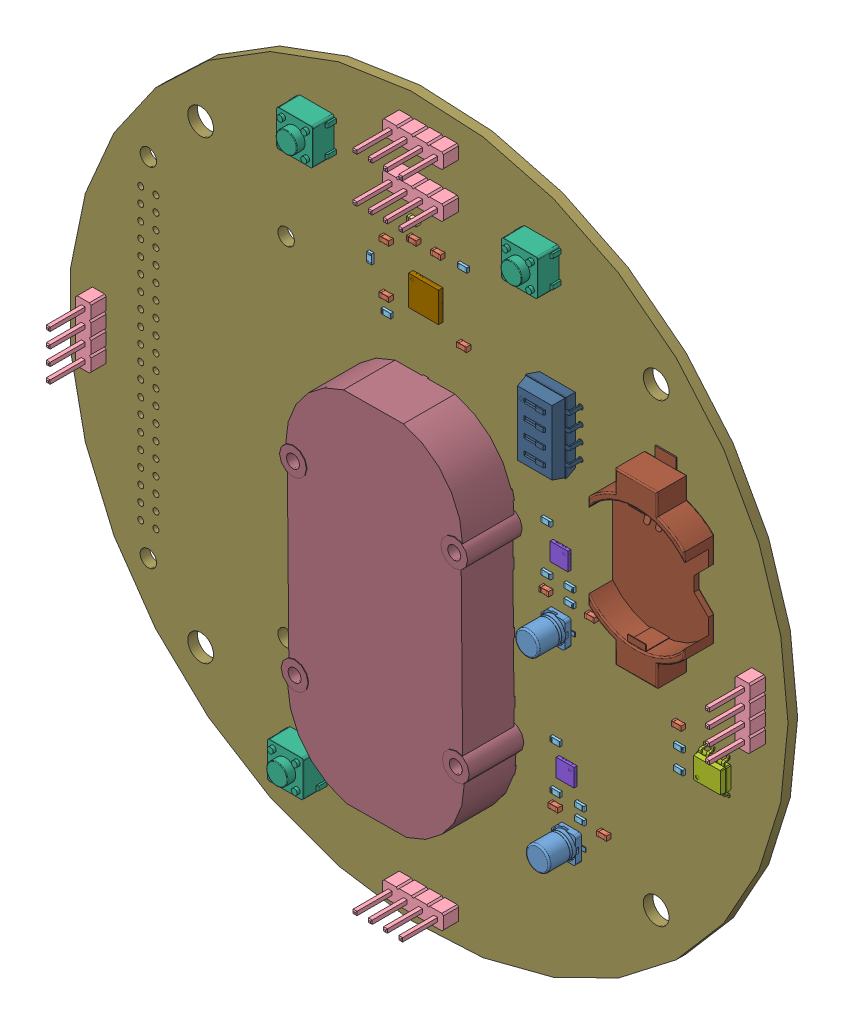
SolidWorks assembly PCB, configuration Default. Lengths in mm.
Overall size (120 120 26.3).
83 component instances, 13 part files, 8 mates.
Components (placement in the parent):
- clockclock.step-1: clockclock.step [Default] at origin size (120 120 12.04)
  - C_Elec_4x5.4.step-1: C_Elec_4x5.4.step [Default] at (21.844 -4.826 1.65) size (5.74 5.46 5.4)
    - COMPOUND.step-1: COMPOUND.step [Default] at origin size (5.74 5.46 5.4)
  - C_Elec_4x5.4.step-2: C_Elec_4x5.4.step [Default] at (23.622 -35.052 1.65) size (5.74 5.46 5.4)
    - COMPOUND.step-1: COMPOUND.step [Default] at origin size (5.74 5.46 5.4)
  - C_0603_1608Metric.step-1: C_0603_1608Metric.step [Default] at (29.718 -30.988 1.65) x (-1 0 0) z (0 0 1) size (1.6 0.8 0.8)
    - SOLID.step-1: SOLID.step [Default] at origin size (1.6 0.8 0.8)
  - C_0603_1608Metric.step-2: C_0603_1608Metric.step [Default] at (27.686 -0.508 1.65) x (-1 0 0) z (0 0 1) size (1.6 0.8 0.8)
    - SOLID.step-1: SOLID.step [Default] at origin size (1.6 0.8 0.8)
  - C_0603_1608Metric.step-3: C_0603_1608Metric.step [Default] at (42.164 -8.89 1.65) size (1.6 0.8 0.8)
    - SOLID.step-1: SOLID.step [Default] at origin size (1.6 0.8 0.8)
  - C_0603_1608Metric.step-4: C_0603_1608Metric.step [Default] at (-6.604 36.83 1.65) size (1.6 0.8 0.8)
    - SOLID.step-1: SOLID.step [Default] at origin size (1.6 0.8 0.8)
  - C_0603_1608Metric.step-5: C_0603_1608Metric.step [Default] at (-6.604 28.702 1.65) size (1.6 0.8 0.8)
    - SOLID.step-1: SOLID.step [Default] at origin size (1.6 0.8 0.8)
  - C_0603_1608Metric.step-6: C_0603_1608Metric.step [Default] at (2.032 39.116 1.65) size (1.6 0.8 0.8)
    - SOLID.step-1: SOLID.step [Default] at origin size (1.6 0.8 0.8)
  - C_0603_1608Metric.step-7: C_0603_1608Metric.step [Default] at (6.35 27.94 1.65) size (1.6 0.8 0.8)
    - SOLID.step-1: SOLID.step [Default] at origin size (1.6 0.8 0.8)
  - C_0603_1608Metric.step-8: C_0603_1608Metric.step [Default] at (-2.032 39.116 1.65) size (1.6 0.8 0.8)
    - SOLID.step-1: SOLID.step [Default] at origin size (1.6 0.8 0.8)
  - L_0603_1608Metric.step-1: L_0603_1608Metric.step [Default] at (-2.032 41.91 1.65) size (1.6 0.8 0.8)
    - SOLID-0.step-1: SOLID-0.step [Default] at origin size (1.6 0.8 0.8)
  - PinHeader_1x04_P2.54mm_Vertical.step-1: PinHeader_1x04_P2.54mm_Vertical.step [Default] at (55 3.81 1.65) size (2.54 10.16 11.54)
    - SOLID-1.step-1: SOLID-1.step [Default] at origin size (2.54 10.16 11.54)
  - PinHeader_1x04_P2.54mm_Vertical.step-2: PinHeader_1x04_P2.54mm_Vertical.step [Default] at (-3.81 55 1.65) x (0 1 0) z (0 0 1) size (2.54 10.16 11.54)
    - SOLID-1.step-1: SOLID-1.step [Default] at origin size (2.54 10.16 11.54)
  - PinHeader_1x04_P2.54mm_Vertical.step-3: PinHeader_1x04_P2.54mm_Vertical.step [Default] at (-3.81 -55 1.65) x (0 1 0) z (0 0 1) size (2.54 10.16 11.54)
    - SOLID-1.step-1: SOLID-1.step [Default] at origin size (2.54 10.16 11.54)
  - PinHeader_1x04_P2.54mm_Vertical.step-4: PinHeader_1x04_P2.54mm_Vertical.step [Default] at (-55 3.81 1.65) size (2.54 10.16 11.54)
    - SOLID-1.step-1: SOLID-1.step [Default] at origin size (2.54 10.16 11.54)
  - PinHeader_1x04_P2.54mm_Vertical.step-5: PinHeader_1x04_P2.54mm_Vertical.step [Default] at (-3.81 47.498 1.65) x (0 1 0) z (0 0 1) size (2.54 10.16 11.54)
    - SOLID-1.step-1: SOLID-1.step [Default] at origin size (2.54 10.16 11.54)
  - R_0603_1608Metric.step-1: R_0603_1608Metric.step [Default] at (25.654 -30.988 1.65) x (-1 0 0) z (0 0 1) size (1.6 0.8 0.45)
    - SOLID-2.step-1: SOLID-2.step [Default] at origin size (1.6 0.8 0.45)
  - R_0603_1608Metric.step-2: R_0603_1608Metric.step [Default] at (23.876 -0.508 1.65) x (-1 0 0) z (0 0 1) size (1.6 0.8 0.45)
    - SOLID-2.step-1: SOLID-2.step [Default] at origin size (1.6 0.8 0.45)
  - R_0603_1608Metric.step-3: R_0603_1608Metric.step [Default] at (25.654 -28.956 1.65) size (1.6 0.8 0.45)
    - SOLID-2.step-1: SOLID-2.step [Default] at origin size (1.6 0.8 0.45)
  - R_0603_1608Metric.step-4: R_0603_1608Metric.step [Default] at (23.876 1.778 1.65) size (1.6 0.8 0.45)
    - SOLID-2.step-1: SOLID-2.step [Default] at origin size (1.6 0.8 0.45)
  - R_0603_1608Metric.step-5: R_0603_1608Metric.step [Default] at (21.59 -28.956 1.65) x (-1 0 0) z (0 0 1) size (1.6 0.8 0.45)
    - SOLID-2.step-1: SOLID-2.step [Default] at origin size (1.6 0.8 0.45)
  - R_0603_1608Metric.step-6: R_0603_1608Metric.step [Default] at (20.066 1.778 1.65) x (-1 0 0) z (0 0 1) size (1.6 0.8 0.45)
    - SOLID-2.step-1: SOLID-2.step [Default] at origin size (1.6 0.8 0.45)
  - R_0603_1608Metric.step-7: R_0603_1608Metric.step [Default] at (21.59 -21.59 1.65) x (-1 0 0) z (0 0 1) size (1.6 0.8 0.45)
    - SOLID-2.step-1: SOLID-2.step [Default] at origin size (1.6 0.8 0.45)
  - R_0603_1608Metric.step-8: R_0603_1608Metric.step [Default] at (20.066 9.398 1.65) x (-1 0 0) z (0 0 1) size (1.6 0.8 0.45)
    - SOLID-2.step-1: SOLID-2.step [Default] at origin size (1.6 0.8 0.45)
  - R_0603_1608Metric.step-9: R_0603_1608Metric.step [Default] at (-9.398 32.766 1.65) x (0 -1 0) z (0 0 1) size (1.6 0.8 0.45)
    - SOLID-2.step-1: SOLID-2.step [Default] at origin size (1.6 0.8 0.45)
  - SW_PUSH_6mm_H5mm.step-1: SW_PUSH_6mm_H5mm.step [Default] at (-23.3934 -42.6974 1.65) size (7.17 6 8.5)
    - SOLID-3.step-1: SOLID-3.step [Default] at origin size (7.17 6 8.5)
  - SW_PUSH_6mm_H5mm.step-2: SW_PUSH_6mm_H5mm.step [Default] at (-15.5194 44.8818 1.65) x (-1 0 0) z (0 0 1) size (7.17 6 8.5)
    - SOLID-3.step-1: SOLID-3.step [Default] at origin size (7.17 6 8.5)
  - SW_PUSH_6mm_H5mm.step-3: SW_PUSH_6mm_H5mm.step [Default] at (15.6972 49.2506 1.65) size (7.17 6 8.5)
    - SOLID-3.step-1: SOLID-3.step [Default] at origin size (7.17 6 8.5)
  - SOIC-8_3.9x4.9mm_P1.27mm.step-1: SOIC-8_3.9x4.9mm_P1.27mm.step [Default] at (48.26 -12.446 1.65) x (0 1 0) z (0 0 1) size (6 4.9 1.75)
    - SOLID-4.step-1: SOLID-4.step [Default] at origin size (6 4.9 1.75)
  - UQFN-16-1EP_3x3mm_P0.5mm_EP1.75x1.75mm.step-1: UQFN-16-1EP_3x3mm_P0.5mm_EP1.75x1.75mm.step [Default] at (23.368 -25.146 1.65) x (0 -1 0) z (0 0 1) size (3 3 0.52)
    - SOLID-5.step-1: SOLID-5.step [Default] at origin size (3 3 0.52)
  - UQFN-16-1EP_3x3mm_P0.5mm_EP1.75x1.75mm.step-2: UQFN-16-1EP_3x3mm_P0.5mm_EP1.75x1.75mm.step [Default] at (22.352 5.588 1.65) x (0 -1 0) z (0 0 1) size (3 3 0.52)
    - SOLID-5.step-1: SOLID-5.step [Default] at origin size (3 3 0.52)
  - QFN-32-1EP_5x5mm_P0.5mm_EP3.45x3.45mm.step-1: QFN-32-1EP_5x5mm_P0.5mm_EP3.45x3.45mm.step [Default] at (0 31.75 1.65) size (5 5 0.77)
    - SOLID-6.step-1: SOLID-6.step [Default] at origin size (5 5 0.77)
  - C_0603_1608Metric.step-9: C_0603_1608Metric.step [Default] at (20.066 -0.508 1.65) size (1.6 0.8 0.8)
    - SOLID.step-1: SOLID.step [Default] at origin size (1.6 0.8 0.8)
  - C_0603_1608Metric.step-10: C_0603_1608Metric.step [Default] at (21.59 -30.988 1.65) size (1.6 0.8 0.8)
    - SOLID.step-1: SOLID.step [Default] at origin size (1.6 0.8 0.8)
  - R_0603_1608Metric.step-10: R_0603_1608Metric.step [Default] at (42.164 -15.494 1.65) x (-1 0 0) z (0 0 1) size (1.6 0.8 0.45)
    - SOLID-2.step-1: SOLID-2.step [Default] at origin size (1.6 0.8 0.45)
  - R_0603_1608Metric.step-11: R_0603_1608Metric.step [Default] at (42.164 -12.192 1.65) x (-1 0 0) z (0 0 1) size (1.6 0.8 0.45)
    - SOLID-2.step-1: SOLID-2.step [Default] at origin size (1.6 0.8 0.45)
  - R_0603_1608Metric.step-12: R_0603_1608Metric.step [Default] at (6.096 39.116 1.65) x (-1 0 0) z (0 0 1) size (1.6 0.8 0.45)
    - SOLID-2.step-1: SOLID-2.step [Default] at origin size (1.6 0.8 0.45)
  - R_0603_1608Metric.step-13: R_0603_1608Metric.step [Default] at (-6.604 26.162 1.65) x (-1 0 0) z (0 0 1) size (1.6 0.8 0.45)
    - SOLID-2.step-1: SOLID-2.step [Default] at origin size (1.6 0.8 0.45)
  - SW_DIP_SPSTx04_Slide_6.7x11.72mm_W7.62mm_P2.54mm_LowProfile.step-1: SW_DIP_SPSTx04_Slide_6.7x11.72mm_W7.62mm_P2.54mm_LowProfile.step [Default] at (17.78 28.448 1.65) x (0 -1 0) z (0 0 1) size (11.72 7.82 6)
    - SOLID-7.step-1: SOLID-7.step [Default] at origin size (11.72 7.82 6)
  - BatteryHolder_Keystone_1058_1x2032.step-1: BatteryHolder_Keystone_1058_1x2032.step [Default] at (39.878 13.462 1.65) x (0 1 0) z (0 0 1) size (31.86 16 5.08)
    - SOLID-8.step-1: SOLID-8.step [Default] at origin size (31.86 16 5.08)
  - COMPOUND-9.step-1: COMPOUND-9.step [Default] at origin size (120 120 1.6)
- BKA30D-1: BKA30D [Default] at (0.0841 -9.5996 10.6) x (-0.008761 0.999962 0) z (-0.999962 -0.008761 0) size (59.5 26.3 31.4)
Mates (geometry in assembly coordinates):
- Coincident1: coincident anti-aligned: plane of clockclock.step-1/COMPOUND-9.step-1 through (0 0 1.6) normal (0 0 1); plane of BKA30D-1 through (-8.7876 -4.1956 1.6) normal (0 0 -1)
- Concentric1: concentric aligned: cylinder of clockclock.step-1/COMPOUND-9.step-1 through (0 0 -0.8) axis (0 0 1) radius 3; cylinder of BKA30D-1 through (0 0 -4.6) axis (0 0 1) radius 2.85
- Concentric4: concentric anti-aligned: cylinder of BKA30D-1 through (0 0 -9.4) axis (0 0 1) radius 2; cylinder of grootewijzer-1 through (0 0 -7) axis (0 0 -1) radius 2
- Distance1: distance = 0.4 mm anti-aligned: plane of grootewijzer-1 through (0 0 -5) normal (0 0 1); plane of BKA30D-1 through (0 0 -4.6) normal (0 0 -1)
- Concentric5: concentric anti-aligned: cylinder of BKA30D-1 through (0 0 -15.6) axis (0 0 1) radius 0.75; cylinder of kleinewijzer-1 through (0 0 -13.6) axis (0 0 -1) radius 0.74
- Coincident3: coincident aligned: plane of BKA30D-1 through (0 0 -15.6) normal (0 0 -1); plane of kleinewijzer-1 through (0 0 -15.6) normal (0 0 -1)
- Concentric6: concentric anti-aligned: cylinder of BKA30D-1 through (0 0 -4.6) axis (0 0 1) radius 2.85; cylinder of face-1 through (0 0 -2.3372) axis (0 0 -1) radius 2.75
- Coincident4: coincident aligned: plane of BKA30D-1 through (0 0 -4.6) normal (0 0 -1); plane of face-1 through (0 0 -4.6) normal (0 0 -1)
